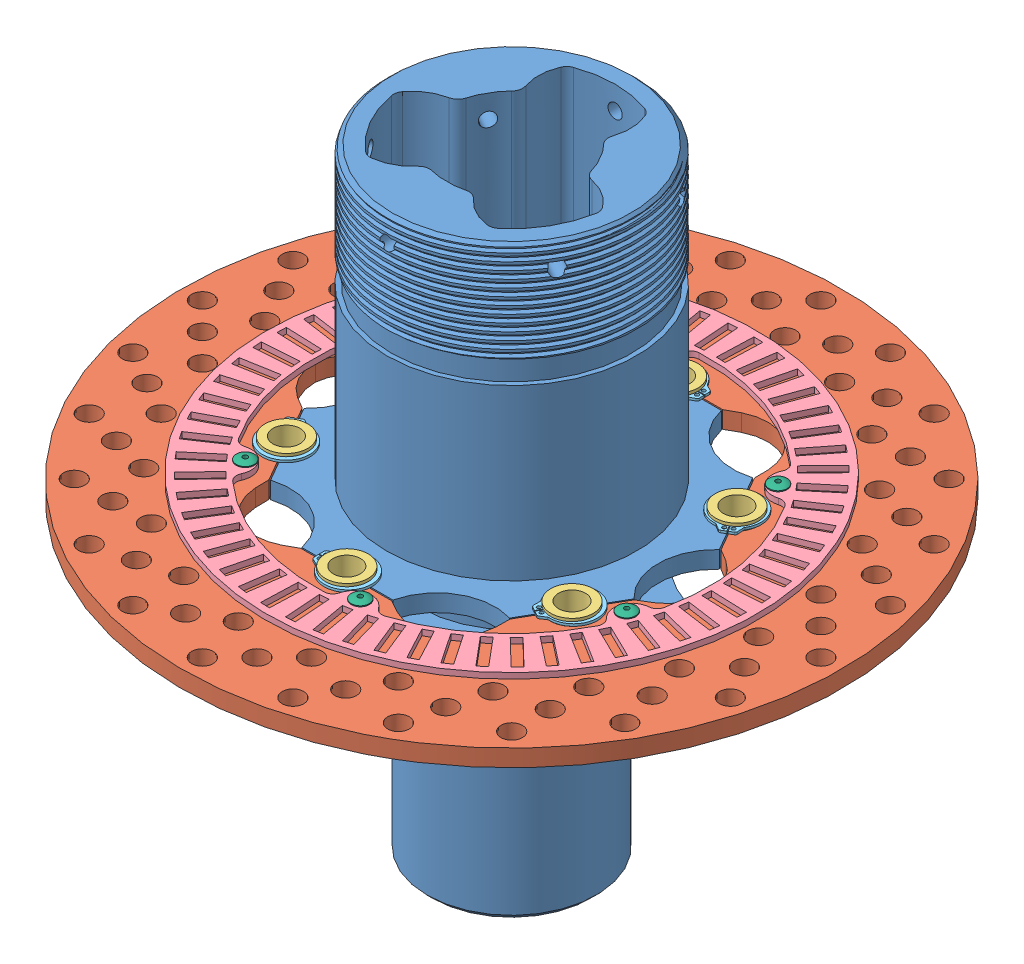
SolidWorks assembly BR-A0000-AB-Rear Brake Assembly, configuration Default No Bobbins. Lengths in mm.
Overall size (251.55 172.72 251.55).
21 component instances, 6 part files, 18 mates.
Components (placement in the parent):
- WT-XA-#####-Tripod Hub-2: WT-XA-#####-Tripod Hub [Default] at origin
- BR-20601-AB-Brake Rotor-1: BR-20601-AB-Brake Rotor [Default] at (0 26.1303 0) x (0.866025 0 -0.5) z (0.5 0 0.866025)
- BR-20603-BA-Floating Bobbins-1: BR-20603-BA-Floating Bobbins [Default] at (39.8696 25.9874 23.0188)
- BR-20603-BA-Floating Bobbins-2: BR-20603-BA-Floating Bobbins [Default] at (0 25.9874 46.0375) x (0.5 0 0.866025) z (-0.866025 0 0.5)
- BR-20603-BA-Floating Bobbins-3: BR-20603-BA-Floating Bobbins [Default] at (-39.8696 25.9874 23.0188) x (-0.5 0 0.866025) z (-0.866025 0 -0.5)
- BR-20603-BA-Floating Bobbins-4: BR-20603-BA-Floating Bobbins [Default] at (-39.8696 25.9874 -23.0188) x (-1 0 0) z (0 0 -1)
- BR-20603-BA-Floating Bobbins-5: BR-20603-BA-Floating Bobbins [Default] at (0 25.9874 -46.0375) x (-0.5 0 -0.866025) z (0.866025 0 -0.5)
- BR-20603-BA-Floating Bobbins-6: BR-20603-BA-Floating Bobbins [Default] at (39.8696 25.9874 -23.0188) x (0.5 0 -0.866025) z (0.866025 0 0.5)
- WT-20104-AB-Rear Sensor Ring-1: WT-20104-AB-Rear Sensor Ring [Default] at (0 30.099 0) x (0.882948 0 -0.469472) z (0 -1 0) size (137 137 1.59)
- 91590A121_External Retaining Ring-1: 91590A121_External Retaining Ring [91590A121] at (-39.8696 29.2354 23.0188) x (0 1 0) z (-0.857167 0 0.515038) size (0.64 14.63 13.25)
- 91590A121_External Retaining Ring-2: 91590A121_External Retaining Ring [91590A121] at (-39.8696 29.2354 -23.0188) x (0 1 0) z (-0.87462 0 -0.48481) size (0.64 14.63 13.25)
- 91590A121_External Retaining Ring-3: 91590A121_External Retaining Ring [91590A121] at (0 29.2354 -46.0375) x (0 1 0) z (-0.017452 0 -0.999848) size (0.64 14.63 13.25)
- 91590A121_External Retaining Ring-4: 91590A121_External Retaining Ring [91590A121] at (39.8696 29.2354 -23.0188) x (0 1 0) z (0.857167 0 -0.515038) size (0.64 14.63 13.25)
- 91590A121_External Retaining Ring-5: 91590A121_External Retaining Ring [91590A121] at (39.8696 29.2354 23.0188) x (0 1 0) z (0.87462 0 0.48481) size (0.64 14.63 13.25)
- 91590A121_External Retaining Ring-6: 91590A121_External Retaining Ring [91590A121] at (0 29.2354 46.0375) x (0 1 0) z (0.017452 0 0.999848) size (0.64 14.63 13.25)
- 97447A110_Aluminum Blind Rivets with Aluminum Mandrel-1: 97447A110_Aluminum Blind Rivets with Aluminum Mandrel [97447A110] at (9.6137 30.099 51.8707) x (-0.302097 0 -0.953277) z (0 1 0) size (5.03 5.03 11.56)
- 97447A110_Aluminum Blind Rivets with Aluminum Mandrel-2: 97447A110_Aluminum Blind Rivets with Aluminum Mandrel [97447A110] at (-40.1145 30.099 34.261) x (0.674514 0 -0.738262) z (0 1 0) size (5.03 5.03 11.56)
- 97447A110_Aluminum Blind Rivets with Aluminum Mandrel-3: 97447A110_Aluminum Blind Rivets with Aluminum Mandrel [97447A110] at (-49.7282 30.099 -17.6097) x (0.976611 0 0.215015) z (0 1 0) size (5.03 5.03 11.56)
- 97447A110_Aluminum Blind Rivets with Aluminum Mandrel-4: 97447A110_Aluminum Blind Rivets with Aluminum Mandrel [97447A110] at (-9.6137 30.099 -51.8707) x (0.302097 0 0.953277) z (0 1 0) size (5.03 5.03 11.56)
- 97447A110_Aluminum Blind Rivets with Aluminum Mandrel-5: 97447A110_Aluminum Blind Rivets with Aluminum Mandrel [97447A110] at (40.1145 30.099 -34.261) x (-0.674514 0 0.738262) z (0 1 0) size (5.03 5.03 11.56)
- 97447A110_Aluminum Blind Rivets with Aluminum Mandrel-6: 97447A110_Aluminum Blind Rivets with Aluminum Mandrel [97447A110] at (49.7282 30.099 17.6097) x (-0.976611 0 -0.215015) z (0 1 0) size (5.03 5.03 11.56)
Mates (geometry in assembly coordinates):
- Concentric1: concentric aligned: cylinder of WT-XA-#####-Tripod Hub-2 through (0 109.474 0) axis (0 -1 0) radius 34.925; cylinder of BR-20601-AB-Brake Rotor-1 through (0 28.5115 0) axis (0 -1 0) radius 92.075
- Concentric2: concentric aligned: cylinder of WT-XA-#####-Tripod Hub-2 through (0 28.5115 46.0375) axis (0 -1 0) radius 5.9531; cylinder of BR-20601-AB-Brake Rotor-1 through (0 28.5115 46.0375) axis (0 -1 0) radius 5.9531
- Coincident1: coincident aligned: plane of WT-XA-#####-Tripod Hub-2 through (0 28.5115 46.0375) normal (0 1 0); plane of BR-20601-AB-Brake Rotor-1 through (0 28.5115 0) normal (0 1 0)
- Concentric4: concentric aligned: cylinder of WT-XA-#####-Tripod Hub-1 through (105.4169 -189.7734 77.9946) axis (0 -1 0) radius 7.9375; cylinder of BR-20603-BA-Floating Bobbins-1 through (110.0519 -107.3831 80.5618) axis (0 -1 0) radius 7.9375
- Coincident2: coincident anti-aligned: plane of BR-20601-AB-Brake Rotor-1 through (59.3794 -193.3453 77.9946) normal (0 -1 0); plane of BR-20603-BA-Floating Bobbins-1 through (110.0519 -109.6215 91.6743) normal (0 1 0)
- Coincident3: coincident anti-aligned: plane of WT-XA-#####-Tripod Hub-1 through (36.3607 -189.7734 117.8642) normal (0 1 0); plane of WT-20104-AB-Sensor Ring-1 through (60.0656 -194.4083 78.8702) normal (0 -1 0)
- Concentric5: concentric anti-aligned: cylinder of WT-XA-#####-Tripod Hub-2 through (34.4344 -187.5405 143.138) axis (0 -1 0) radius 5.9531; cylinder of BR-20603-BA-Floating Bobbins-1 through (34.4344 -185.6037 143.138) axis (0 1 0) radius 3.7704
- Coincident8: coincident anti-aligned: plane of BR-20601-AB-Brake Rotor-1 through (0 23.749 0) normal (0 -1 0); plane of BR-20603-BA-Floating Bobbins-1 through (39.8696 23.749 30.9563) normal (0 1 0)
- Concentric6: concentric anti-aligned: cylinder of BR-20601-AB-Brake Rotor-1 through (0 28.5115 0) axis (0 -1 0) radius 92.075; cylinder of WT-20104-AB-Rear Sensor Ring-1 through (0 28.5115 0) axis (0 1 0) radius 68.5006
- Coincident9: coincident anti-aligned: plane of BR-20601-AB-Brake Rotor-1 through (0 28.5115 0) normal (0 1 0); plane of WT-20104-AB-Rear Sensor Ring-1 through (0 28.5115 0) normal (0 -1 0)
- Concentric7: concentric aligned: cylinder of BR-20601-AB-Brake Rotor-1 through (0 28.5115 46.0375) axis (0 -1 0) radius 5.9531; cylinder of BR-20603-BA-Floating Bobbins-2 through (0 25.9874 46.0375) axis (0 -1 0) radius 5.9531
- Concentric9: concentric aligned: cylinder of BR-20603-BA-Floating Bobbins-3 through (-39.8696 25.9874 23.0188) axis (0 -1 0) radius 5.6261; cylinder of 91590A121_External Retaining Ring-1 through (-39.8696 29.5529 23.0188) axis (0 -1 0) radius 5.4356
- Coincident10: coincident anti-aligned: plane of BR-20603-BA-Floating Bobbins-3 through (-45.0252 28.9179 20.0422) normal (0 1 0); plane of 91590A121_External Retaining Ring-1 through (-39.8696 28.9179 23.0188) normal (0 -1 0)
- Coincident11: coordinate: point of WT-XA-#####-Tripod Hub-2
- Parallel1: parallel aligned: line of WT-XA-#####-Tripod Hub-2 through (-36.7404 28.5115 28.0831) axis (0.5 0 0.866025); line of 91590A121_External Retaining Ring-1 through (-43.705 29.5529 16.3756) axis (0.5 0 0.866025)
- Concentric11: concentric anti-aligned: cylinder of BR-20601-AB-Brake Rotor-1 through (9.6137 23.749 51.8707) axis (0 1 0) radius 1.27; cylinder of 97447A110_Aluminum Blind Rivets with Aluminum Mandrel-1 through (9.6137 20.574 51.8707) axis (0 -1 0) radius 1.1906
- Coincident12: coincident anti-aligned: plane of WT-20104-AB-Rear Sensor Ring-1 through (0 30.099 0) normal (0 1 0); plane of 97447A110_Aluminum Blind Rivets with Aluminum Mandrel-1 through (8.4787 30.099 52.2304) normal (0 -1 0)
- Angle1: planar angle = 0.488692 rad aligned: plane of WT-20104-AB-Rear Sensor Ring-1 through (0 30.099 0) normal (0.469472 0 0.882948)
